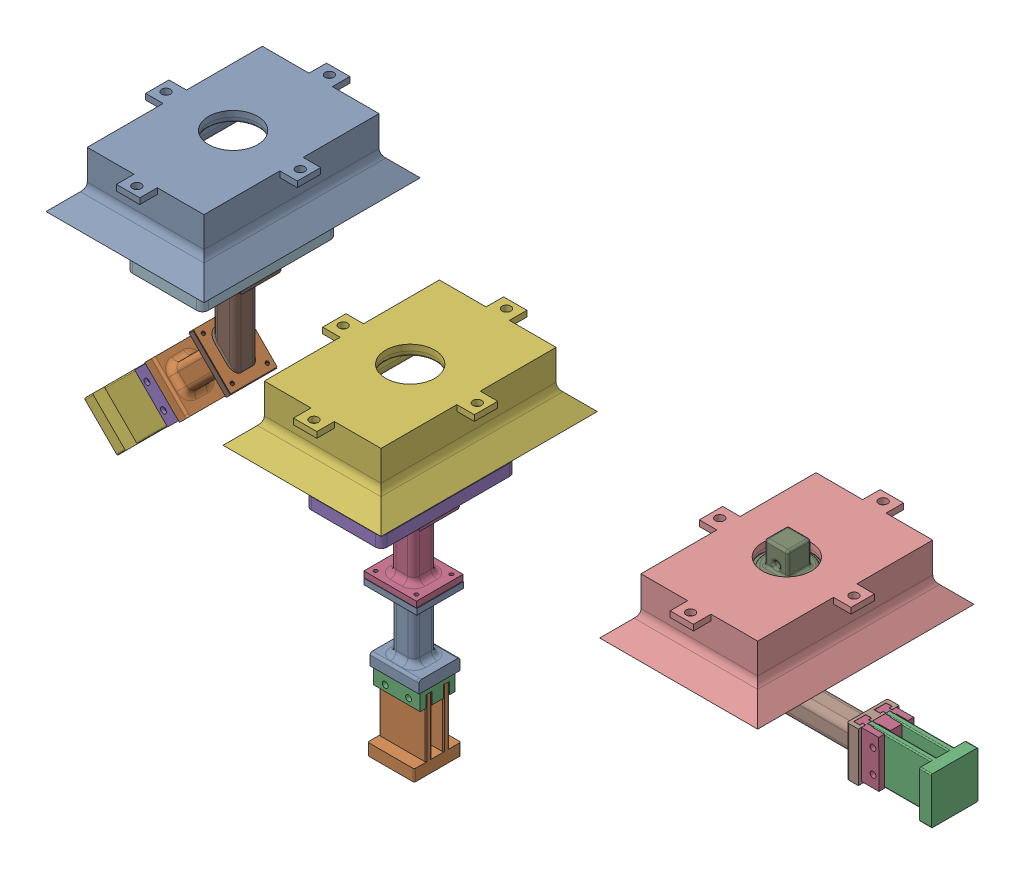
SolidWorks assembly Drop_test_release_system, configuration Default. Lengths in mm.
Overall size (718.98 294.25 282.57).
18 component instances, 6 part files, 0 mates.
Components (placement in the parent):
- connector-1: connector [Default] at (-98.7449 -63.8329 -39.2395) size (45 65 40)
- eurepus_fork-1: eurepus_fork [Default] at (-78.3737 -118.963 -41.7364) x (0 0 -1) z (1 0 0) size (39.95 65 40)
- eurepus_fork_lid-1: eurepus_fork_lid [Default] at (-78.2853 -78.8884 -39.2421) x (0 0 -1) z (1 0 0) size (30 22.5 40)
- connector-2: connector [Default] at (-98.8391 66.6696 -39.0677) x (1 0 0) z (0 0 -1) size (45 65 40)
- eurepus_roof-1: eurepus_roof [Default] at (-113.9242 76.7461 -39.0821) x (1 0 0) z (0 0 -1) size (65 42.5 115)
- net_mount-1: net_mount [Default] at (-81.3428 160.2411 -38.7218) x (1 0 0) z (0 0 -1) size (135.36 47.68 185.36)
- connector_45_pitch-1: connector_45_pitch [Default] at (166.7247 59.9803 -136.3372) x (-1 0 0) z (0 0 1) size (42 89.45 40)
- connector_45_pitch-2: connector_45_pitch [Default] at (223.6787 2.4764 -135.199) x (0 -1 0) z (0 0 -1) size (42 89.45 40)
- eurepus_roof-2: eurepus_roof [Default] at (112.0906 70.023 -136.3657) x (1 0 0) z (0 0 -1) size (65 42.5 115)
- net_mount-2: net_mount [Default] at (144.1832 81.4 -135.932) x (1 0 0) z (0 0 -1) size (135.36 47.68 185.36)
- connector_45_pitch-3: connector_45_pitch [Default] at (-343.8758 73.5961 -131.2255) x (1 0 0) z (0 0 -1) size (42 89.45 40)
- eurepus_roof-3: eurepus_roof [Default] at (-359.3585 83.6019 -131.268) x (1 0 0) z (0 0 -1) size (65 42.5 115)
- net_mount-3: net_mount [Default] at (-325.5961 165.2913 -131.2683) x (1 0 0) z (0 0 -1) size (135.36 47.68 185.36)
- connector-4: connector [Default] at (-384.1849 -27.5829 -131.6174) x (0.707107 -0.707107 0) z (0 0 1) size (45 65 40)
- eurepus_fork-2: eurepus_fork [Default] at (278.6925 -17.4116 -132.7095) x (0 0 1) z (0 -1 0) size (39.95 65 40)
- eurepus_fork_lid-2: eurepus_fork_lid [Default] at (238.7453 -17.4986 -135.2018) x (0.002077 -0.001566 -0.999997) z (-0.006551 0.999977 -0.001579) size (30 22.5 40)
- eurepus_fork_lid-3: eurepus_fork_lid [Default] at (-380.2225 -53.0807 -130.5977) x (0 0 1) z (-0.707107 0.707107 0) size (30 22.5 40)
- eurepus_fork-3: eurepus_fork [Default] at (-409.0704 -81.5031 -130.9247) x (0 0 -1) z (0.707107 -0.707107 0) size (39.95 65 40)
